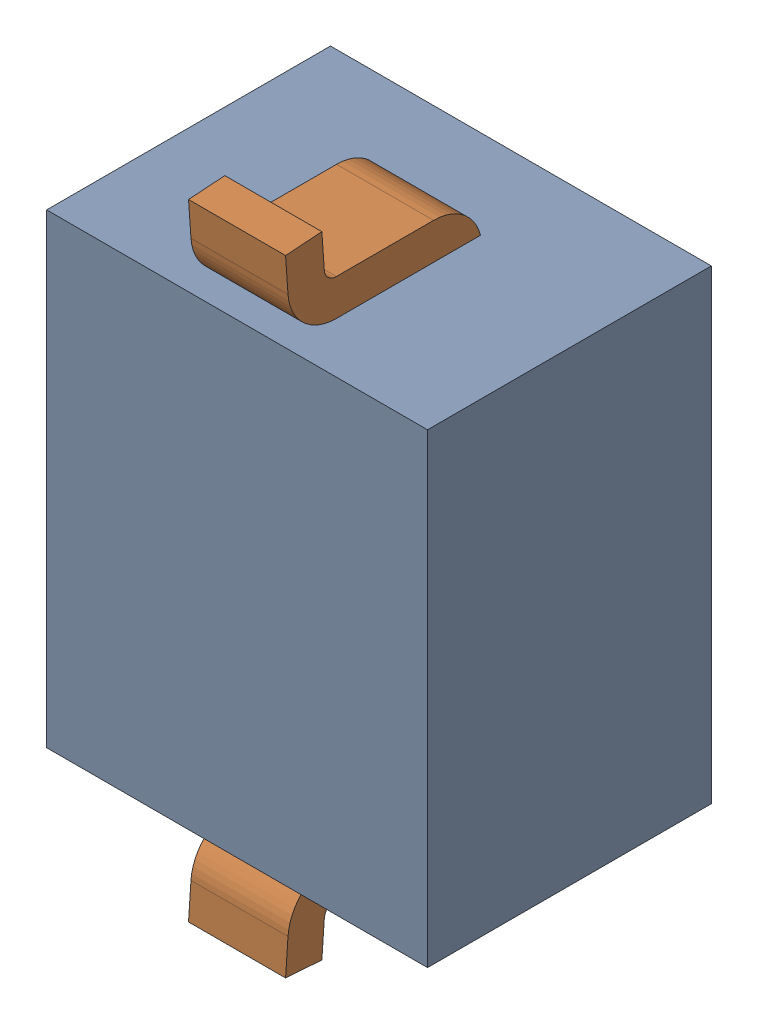
SolidWorks assembly D4, configuration Default. Lengths in mm.
Overall size (1.57 2.6 1.17).
3 component instances, 2 part files, 0 mates.
Components (placement in the parent):
- 1088885248-1: 1088885248 [Default] at (7.375 3.875 -2.814) size (1.57 1.92 1.17)
  - Extruded-38-1: Extruded-38 [Default] at origin size (1.57 1.92 1.17)
- SOD323-1: SOD323 [Default] at (7.3749 3.8749 -1.644) x (0 1 0) z (0 0 -1) size (2.6 1.35 1.1)
